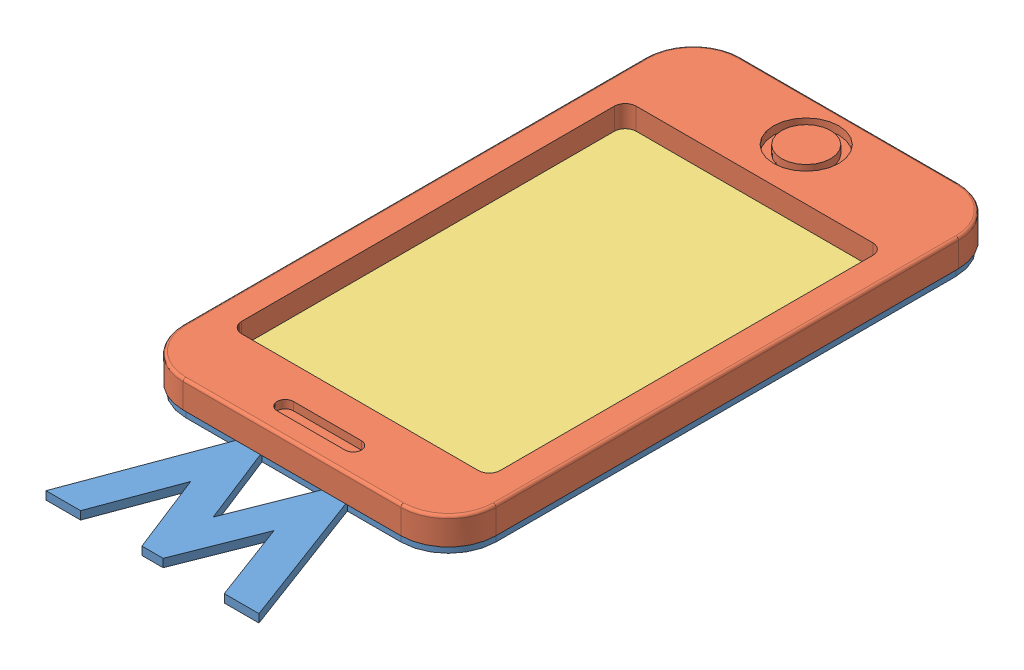
SolidWorks assembly assembly fotolijst, configuration Default. Lengths in mm.
Overall size (115 13 255.88).
3 component instances, 3 part files, 6 mates.
Components (placement in the parent):
- hang plaatje-1: hang plaatje [Default] at (20.1394 128.0094 239.9417) size (114 3 255.88)
- Frees Telefoon fotolijst-1: Frees Telefoon fotolijst [Default] at (125.1394 131.0094 70.9417) x (-1 0 0) z (0 1 0) size (115 205 10)
- glasplaatje-1: glasplaatje [Default] at (31.1394 134.0094 71.9417) x (1 0 0) z (0 -1 0) size (94 144 3)
Mates (geometry in assembly coordinates):
- Coincident1: coincident: plane of hang plaatje-1 through (37.6394 131.0094 222.4417) normal (0 1 0); plane of Frees Telefoon fotolijst-1 through (117.6394 131.0094 53.4417) normal (0 -1 0)
- Coincident2: coincident: line of hang plaatje-1 through (116.6394 131.0094 35.9417) axis (-1 0 0); line of Frees Telefoon fotolijst-1 through (117.6394 131.0094 35.9417) axis (-1 0 0)
- Coincident3: coincident: line of hang plaatje-1 through (20.1394 131.0094 53.4417) axis (0 0 1); line of Frees Telefoon fotolijst-1 through (20.1394 131.0094 53.4417) axis (0 0 1)
- Coincident4: coincident: plane of Frees Telefoon fotolijst-1 through (125.1394 141.0094 215.9417) normal (0 0 -1); plane of glasplaatje-1 through (31.1394 131.0094 215.9417) normal (0 0 1)
- Coincident6: coincident: plane of Frees Telefoon fotolijst-1 through (125.1394 141.0094 70.9417) normal (-1 0 0); plane of glasplaatje-1 through (125.1394 131.0094 71.9417) normal (1 0 0)
- Coincident7: coincident: plane of hang plaatje-1 through (37.6394 131.0094 222.4417) normal (0 1 0); plane of glasplaatje-1 through (31.1394 131.0094 71.9417) normal (0 -1 0)
